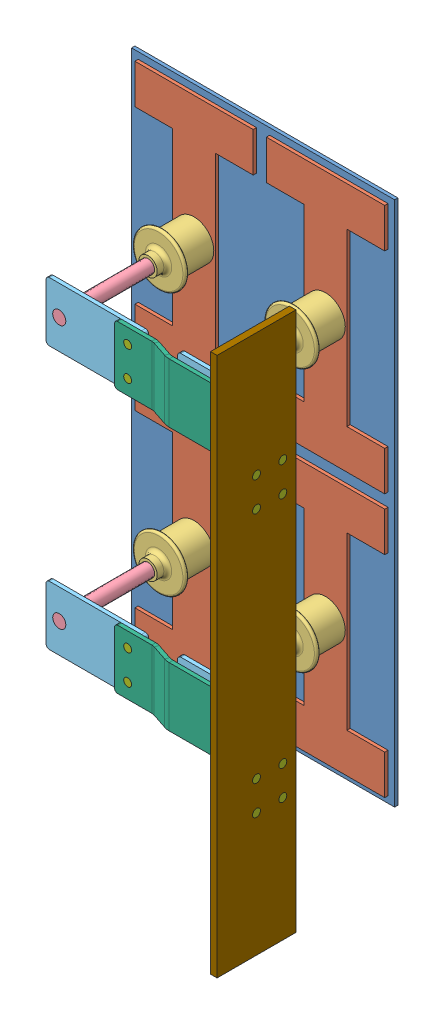
SolidWorks assembly busbar_assembly, configuration Default. Lengths in mm.
Overall size (480 820 355).
38 component instances, 9 part files, 31 mates.
Components (placement in the parent):
- cell_grid_top-1: cell_grid_top [Default] at origin size (400 800 5)
- spine-2: spine [Default] at (-100 -200 5) x (0 1 0) z (0 0 1) size (380 180 5)
- spine-3: spine [Default] at (-100 200 5) x (0 1 0) z (0 0 1) size (380 180 5)
- spine-4: spine [Default] at (100 -200 5) x (0 1 0) z (0 0 1) size (380 180 5)
- spine-5: spine [Default] at (100 200 5) x (0 1 0) z (0 0 1) size (380 180 5)
- central_column-1: central_column [Default] at (-100 -200 10) x (0 1 0) z (0 0 1) size (80 80 70)
- rod-1: rod [Default] at (-100 -200 55) size (20 20 160)
- rod_connector-1: rod_connector [Default] at (-120 -245 209) size (150 90 6)
- rod_connector-2: rod_connector [Default] at (-120 155 209) size (150 90 6)
- rod_connector-3: rod_connector [Default] at (80 -245 209) size (150 90 6)
- rod_connector-4: rod_connector [Default] at (80 155 209) size (150 90 6)
- angle_connector-1: angle_connector [Default] at (-10 -245 215) size (240 90 16)
- angle_connector-2: angle_connector [Default] at (-10 155 215) size (240 90 16)
- bolt-1: bolt [short] at (10 -222.5 209) size (12 12 12)
- bolt-2: bolt [short] at (10 -177.5 209) size (12 12 12)
- bolt-3: bolt [short] at (10 222.5 209) size (12 12 12)
- bolt-4: bolt [short] at (10 177.5 209) size (12 12 12)
- bolt-5: bolt [long] at (210 -222.5 209) size (12 12 22)
- bolt-6: bolt [long] at (210 -177.5 209) size (12 12 22)
- bolt-7: bolt [long] at (210 222.5 209) size (12 12 22)
- bolt-8: bolt [long] at (210 177.5 209) size (12 12 22)
- rod-5: rod [Default] at (-100 200 55) size (20 20 160)
- rod-6: rod [Default] at (100 -200 55) size (20 20 160)
- rod-7: rod [Default] at (100 200 55) size (20 20 160)
- central_column-5: central_column [Default] at (-100 200 10) x (0 1 0) z (0 0 1) size (80 80 70)
- central_column-6: central_column [Default] at (100 -200 10) x (0 1 0) z (0 0 1) size (80 80 70)
- central_column-7: central_column [Default] at (100 200 10) x (0 1 0) z (0 0 1) size (80 80 70)
- elbow_connector-1: elbow_connector [Default] at (190 -155 215) size (80 90 100)
- elbow_connector-2: elbow_connector [Default] at (190 245 215) size (80 90 100)
- intercell_busbar-2: intercell_busbar [Default] at (280 -410 235) x (0 1 0) z (0 0 1) size (820 10 120)
- bolt-9: bolt [medium] at (260 -177.5 295) x (0 0 -1) z (1 0 0) size (12 12 20)
- bolt-10: bolt [medium] at (260 -177.5 255) x (0 0 -1) z (1 0 0) size (12 12 20)
- bolt-11: bolt [medium] at (260 -222.5 295) x (0 0 -1) z (1 0 0) size (12 12 20)
- bolt-12: bolt [medium] at (260 -222.5 255) x (0 0 -1) z (1 0 0) size (12 12 20)
- bolt-13: bolt [medium] at (260 222.5 295) x (0 0 -1) z (1 0 0) size (12 12 20)
- bolt-14: bolt [medium] at (260 222.5 255) x (0 0 -1) z (1 0 0) size (12 12 20)
- bolt-15: bolt [medium] at (260 177.5 295) x (0 0 -1) z (1 0 0) size (12 12 20)
- bolt-16: bolt [medium] at (260 177.5 255) x (0 0 -1) z (1 0 0) size (12 12 20)
Mates (geometry in assembly coordinates):
- Coincident1: coordinate: point of cell_grid_top-1; point of assembly
- Coincident3: coincident: plane of cell_grid_top-1 through (0 0 5) normal (0 0 1); plane of spine-2 through (-100 -200 5) normal (0 0 -1)
- Distance1: distance = 10 mm: plane of spine-2 through (-190 -390 10) normal (-1 0 0); plane of cell_grid_top-1 through (-200 400 5) normal (-1 0 0)
- Distance2: distance = 10 mm: plane of spine-2 through (-10 -390 10) normal (0 -1 0); plane of cell_grid_top-1 through (-200 -400 5) normal (0 -1 0)
- Coincident4: coincident: plane of spine-3 through (-100 200 10) normal (0 0 1); plane of central_column-1 through (-100 -170 10) normal (0 0 -1)
- Coincident11: coordinate: point of spine-2; point of central_column-1
- Coincident12: coincident: plane of central_column-1 through (-100 -200 55) normal (0 0 1); plane of rod-1 through (-100 -200 55) normal (0 0 -1)
- Concentric1: concentric: cylinder of central_column-1 through (-100 -200 10) axis (0 0 -1) radius 10; cylinder of rod-1 through (-100 -200 215) axis (0 0 -1) radius 10
- Coincident13: coincident: plane of rod-1 through (-100 -200 215) normal (0 0 1); plane of rod_connector-1 through (25 -160 215) normal (0 0 1)
- Concentric2: concentric: cylinder of rod-1 through (-100 -200 215) axis (0 0 -1) radius 10; cylinder of rod_connector-1 through (-100 -200 215) axis (0 0 1) radius 10
- Coincident15: coincident: plane of rod_connector-1 through (25 -160 215) normal (0 0 1); plane of angle_connector-1 through (-10 -245 215) normal (0 0 -1)
- Concentric4: concentric: cylinder of rod_connector-1 through (10 -222.5 215) axis (0 0 1) radius 6; cylinder of angle_connector-1 through (10 -222.5 221) axis (0 0 1) radius 6
- Concentric5: concentric: cylinder of rod_connector-1 through (10 -177.5 215) axis (0 0 1) radius 6; cylinder of angle_connector-1 through (10 -177.5 221) axis (0 0 1) radius 6
- Coincident16: coincident: plane of angle_connector-1 through (-10 -245 221) normal (0 0 1); plane of bolt-1 through (10 -222.5 221) normal (0 0 1)
- Concentric6: concentric: cylinder of angle_connector-1 through (10 -222.5 221) axis (0 0 1) radius 6; cylinder of bolt-1 through (10 -222.5 221) axis (0 0 -1) radius 6
- Coincident17: coincident: plane of angle_connector-1 through (-10 -245 221) normal (0 0 1); plane of bolt-2 through (10 -177.5 221) normal (0 0 1)
- Concentric7: concentric: cylinder of angle_connector-1 through (10 -177.5 221) axis (0 0 1) radius 6; cylinder of bolt-2 through (10 -177.5 221) axis (0 0 -1) radius 6
- Coincident19: coincident: plane of angle_connector-1 through (83.2456 -245 231) normal (0 0 1); plane of bolt-5 through (210 -222.5 231) normal (0 0 1)
- Coincident20: coincident: plane of angle_connector-1 through (83.2456 -245 231) normal (0 0 1); plane of bolt-6 through (210 -177.5 231) normal (0 0 1)
- Concentric10: concentric: cylinder of angle_connector-1 through (210 -222.5 231) axis (0 0 1) radius 6; cylinder of bolt-5 through (210 -222.5 231) axis (0 0 -1) radius 6
- Concentric11: concentric: cylinder of angle_connector-1 through (210 -177.5 231) axis (0 0 1) radius 6; cylinder of bolt-6 through (210 -177.5 231) axis (0 0 -1) radius 6
- Coincident21: coincident: plane of rod_connector-3 through (225 -160 215) normal (0 0 1); plane of rod-6 through (100 -200 215) normal (0 0 1)
- Concentric12: concentric: cylinder of rod-6 through (100 -200 215) axis (0 0 -1) radius 10; cylinder of rod_connector-3 through (100 -200 215) axis (0 0 1) radius 10
- Coincident22: coincident: plane of rod_connector-3 through (225 -160 215) normal (0 0 1); plane of elbow_connector-1 through (190 -155 215) normal (0 0 -1)
- Width1: width: plane of elbow_connector-1 through (190 -245 215) normal (0 -1 0); plane of elbow_connector-1 through (190 -155 215) normal (0 1 0); plane of rod_connector-3 through (85 -245 215) normal (0 -1 0); plane of rod_connector-3 through (85 -155 215) normal (0 1 0)
- Concentric13: concentric: cylinder of rod_connector-3 through (210 -222.5 215) axis (0 0 1) radius 6; cylinder of elbow_connector-1 through (210 -222.5 225) axis (0 0 1) radius 6
- Coincident23: coincident: plane of elbow_connector-1 through (270 -155 235) normal (1 0 0); plane of intercell_busbar-2 through (270 -410 235) normal (-1 0 0)
- Width2: width: plane of intercell_busbar-2 through (270 -410 235) normal (0 -1 0); plane of intercell_busbar-2 through (270 410 235) normal (0 1 0); plane of cell_grid_top-1 through (-200 400 5) normal (0 1 0); plane of cell_grid_top-1 through (-200 -400 5) normal (0 -1 0)
- Coincident24: coincident: line of elbow_connector-1 through (270 -245 235) axis (0 1 0); plane of intercell_busbar-2 through (270 -410 235) normal (0 0 -1)
- Coincident25: coincident: plane of elbow_connector-1 through (260 -155 235) normal (-1 0 0); plane of bolt-9 through (260 -177.5 295) normal (-1 0 0)
- Concentric14: concentric: cylinder of elbow_connector-1 through (260 -177.5 295) axis (-1 0 0) radius 6; cylinder of bolt-9 through (280 -177.5 295) axis (-1 0 0) radius 6
